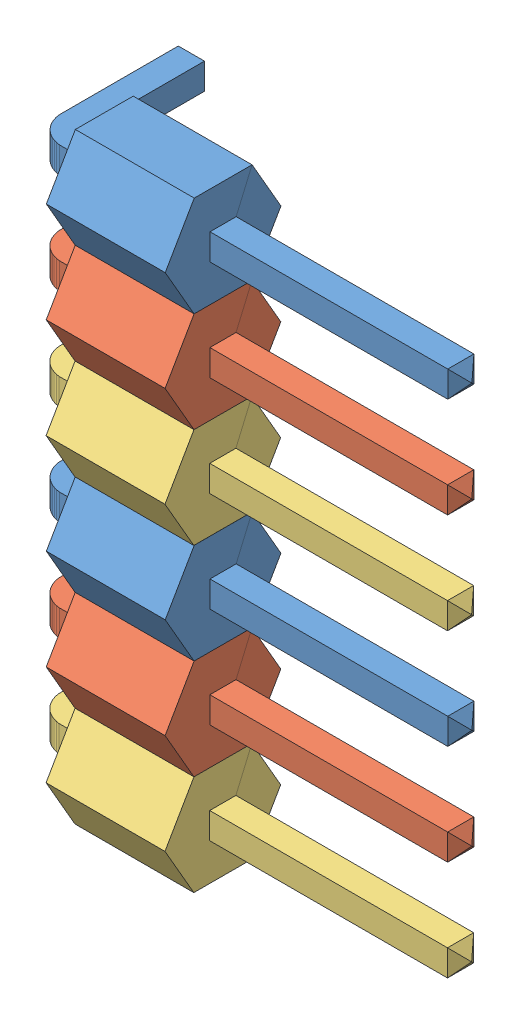
SolidWorks assembly 1X06SMD, configuration Default. Lengths in mm.
Overall size (10.7 15.51 4.98).
8 component instances, 3 part files, 0 mates.
Components (placement in the parent):
- PIN_HEADER_L-ANGLE-1: PIN_HEADER_L-ANGLE [Default] at (0 3.7803 0) x (0 0 -1) z (1 0 0) size (4.98 7.95 10.7)
  - Group_28-1: Group_28 [Default] at (0.0033 2.5199 0) size (4.97 2.91 10.7)
  - Group_25-1: Group_25 [Default] at origin size (4.97 2.91 10.7)
  - Group_29-1: Group_29 [Default] at (-0.0033 -2.5199 0) size (4.97 2.91 10.7)
- PIN_HEADER_L-ANGLE-2: PIN_HEADER_L-ANGLE [Default] at (0 -3.7803 0) x (0 0 -1) z (1 0 0) size (4.98 7.95 10.7)
  - Group_28-1: Group_28 [Default] at (0.0033 2.5199 0) size (4.97 2.91 10.7)
  - Group_25-1: Group_25 [Default] at origin size (4.97 2.91 10.7)
  - Group_29-1: Group_29 [Default] at (-0.0033 -2.5199 0) size (4.97 2.91 10.7)
